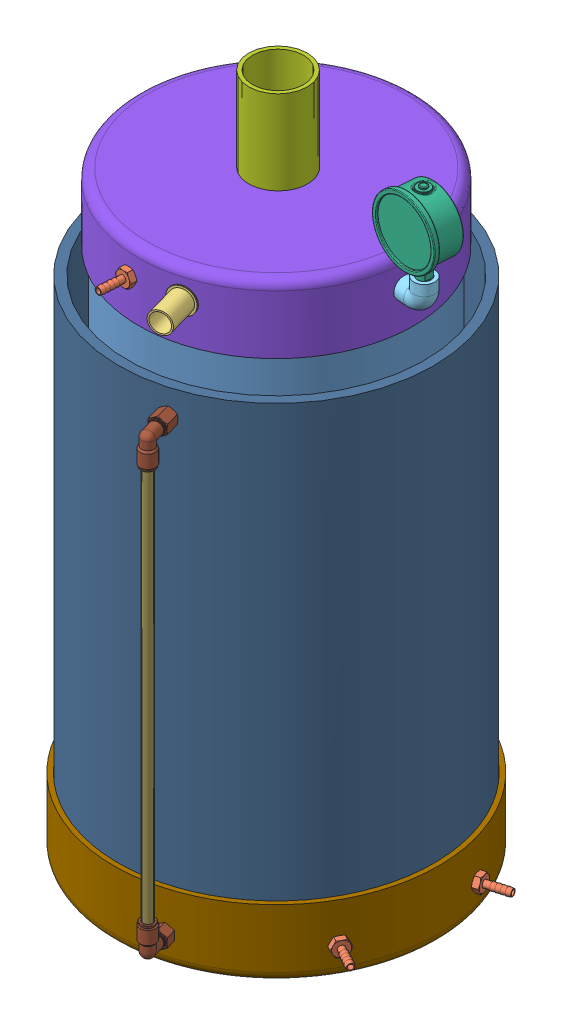
SolidWorks assembly GA, configuration Default. Lengths in mm.
Overall size (619.06 711.2 619.06).
27 component instances, 13 part files, 1 mates.
Components (placement in the parent):
- Top Assembly-1: Top Assembly [Default] at (-37.9382 248.6814 -16.604) size (344.44 711.2 318.42)
  - PI-002-1: PI-002 [Default<As Machined>] at (-41.0436 -593.4608 26.9612) x (0.997588 0 0.069407) z (0 -1 0) size (273.05 273.05 620)
  - 5372K112_DURABLE NYLON EXTRA-GRIP BARBED TUBE FITTING-1: 5372K112_DURABLE NYLON EXTRA-GRIP BARBED TUBE FITTING [5372K112] at (-51.4765 1.1392 176.914) x (-0.069407 0 0.997588) z (-0.863937 0.5 -0.060108) size (43.05 17.6 15.24)
  - 9173K740_THK-WALL DK GRAY PVC THRD-ONE-END PIPE NIPPLE-1: 9173K740_THK-WALL DK GRAY PVC THRD-ONE-END PIPE NIPPLE [9173K74] at (7.021 1.1392 194.3612) x (0.275974 0 0.961165) z (-0.72412 -0.657588 0.207913) size (51.34 27.61 27.43)
  - 4882K110_THICK-WALL DARK GRAY PVC THREADED PIPE NIPPLE-1: 4882K110_THICK-WALL DARK GRAY PVC THREADED PIPE NIPPLE [4882K11] at (101.258 1.1392 36.8618) x (0.997588 0 0.069407) z (-0.068883 -0.122609 0.990062) size (22.92 14.28 14.5)
  - 4596K121_THICK-WALL DARK GRAY PVC PIPE FITTING-1: 4596K121_THICK-WALL DARK GRAY PVC PIPE FITTING [4596K121] at (122.5425 1.1392 38.3427) x (0.997588 0 0.069407) z (-0.069407 0 0.997588) size (32.42 32.42 21.59)
  - 3795K133_STAINLESS STEEL GAUGE-1: 3795K133_STAINLESS STEEL GAUGE [3795K133] at (123.2653 70.4812 27.9538) x (0.997588 0 0.069407) z (-0.069407 0 0.997588) size (69.09 95.73 30.73)
  - PI-003-1: PI-003 [Default<As Machined>] at (-40.9313 -542.6608 25.2788) x (1 0 0) z (0 -1 0) size (60.32 60.32 660.4)
  - 2051K124_CHEMICAL-RESISTANT PVC DUCT - 10inch-3: 2051K124_CHEMICAL-RESISTANT PVC DUCT - 10inch [2051K124] at (-41.0436 -38.5483 26.9612) size (282.97 69.85 282.97)
- Bottom assembly-1: Bottom assembly [Default] at (-55.7763 -319.1166 13.4244) x (0.468435 0 -0.883498) z (-0.883498 0 -0.468435) size (457.9 512.76 457.9)
  - 2051K124_CHEMICAL-RESISTANT PVC DUCT-1: 2051K124_CHEMICAL-RESISTANT PVC DUCT [2051K124] at (-8.1604 -60.8789 21.9388) size (333.77 69.85 333.77)
  - PI-001-1: PI-001 [Default<As Machined>] at (-8.1604 -503.7914 21.9388) x (0.693013 0 -0.720925) z (-0.720925 0 -0.693013) size (323.85 508 323.85)
  - 5372K112_DURABLE NYLON EXTRA-GRIP BARBED TUBE FITTING-1: 5372K112_DURABLE NYLON EXTRA-GRIP BARBED TUBE FITTING [5372K112] at (113.5188 -21.1914 -104.6413) x (0.693013 0 -0.720925) z (-0.624339 0.5 -0.600167) size (43.05 17.6 15.24)
  - 5372K112_DURABLE NYLON EXTRA-GRIP BARBED TUBE FITTING-2: 5372K112_DURABLE NYLON EXTRA-GRIP BARBED TUBE FITTING [5372K112] at (-11.6267 -21.1914 -153.6505) x (-0.019737 0 -0.999805) z (0.865857 0.5 -0.017093) size (43.05 17.6 15.24)
  - 4882K110_THICK-WALL DARK GRAY PVC THREADED PIPE NIPPLE-1: 4882K110_THICK-WALL DARK GRAY PVC THREADED PIPE NIPPLE [4882K11] at (-124.7915 -21.1914 -90.1766) x (-0.720925 0 -0.693013) z (0.026932 0.999245 -0.028016) size (22.92 14.28 14.5)
  - 4882K110_THICK-WALL DARK GRAY PVC THREADED PIPE NIPPLE-2: 4882K110_THICK-WALL DARK GRAY PVC THREADED PIPE NIPPLE [4882K11] at (-124.7915 -478.3914 -90.1766) x (-0.720925 0 -0.693013) z (-0.121421 0.984531 0.126312) size (22.92 14.28 14.5)
  - 5779K638_PUSH-TO-CONNECT TUBE FITTING FOR AIR-1: 5779K638_PUSH-TO-CONNECT TUBE FITTING FOR AIR [5779K638] at (-124.7915 -478.3914 -90.1766) x (-0.693013 0 0.720925) z (0.720925 0 0.693013) size (16 35.65 39.07)
  - 5779K638_PUSH-TO-CONNECT TUBE FITTING FOR AIR-2: 5779K638_PUSH-TO-CONNECT TUBE FITTING FOR AIR [5779K638] at (-124.7915 -21.1914 -90.1766) x (0.693013 0 -0.720925) z (0.720925 0 0.693013) size (16 35.65 39.07)
  - 5233K520_MASTERKLEER PVC TUBING-1: 5233K520_MASTERKLEER PVC TUBING [5233K52] at (-146.8568 -252.8394 -111.3877) x (0 1 0) z (0.000774 0 1) size (410.46 9.53 9.53)
  - PI-004-1: PI-004 [Default<As Machined>] at (-8.4065 -97.3914 31.4606) x (0.958916 0 0.28369) z (-0.28369 0 0.958916) size (28.23 50.8 10.1)
  - PI-004-2: PI-004 [Default<As Machined>] at (-4.6725 -97.3914 13.0754) x (-0.958916 0 -0.28369) z (0.28369 0 -0.958916) size (28.23 50.8 10.1)
  - PI-004-3: PI-004 [Default<As Machined>] at (-17.4948 -97.3914 20.043) x (-0.28369 0 0.958916) z (-0.958916 0 -0.28369) size (28.23 50.8 10.1)
  - PI-004-4: PI-004 [Default<As Machined>] at (1.174 -97.3914 23.8346) x (0.28369 0 -0.958916) z (0.958916 0 0.28369) size (28.23 50.8 10.1)
  - PI-004-6: PI-004 [Default<As Machined>] at (-4.6725 -452.9914 13.0754) x (-0.958916 0 -0.28369) z (0.28369 0 -0.958916) size (28.23 50.8 10.1)
  - PI-004-9: PI-004 [Default<As Machined>] at (-17.4948 -452.9914 20.043) x (-0.28369 0 0.958916) z (-0.958916 0 -0.28369) size (28.23 50.8 10.1)
  - PI-004-13: PI-004 [Default<As Machined>] at (-8.4065 -452.9914 31.4606) x (0.958916 0 0.28369) z (-0.28369 0 0.958916) size (28.23 50.8 10.1)
  - PI-004-14: PI-004 [Default<As Machined>] at (1.174 -452.9914 23.8346) x (0.28369 0 -0.958916) z (0.958916 0 0.28369) size (28.23 50.8 10.1)
Mates (geometry in assembly coordinates):
- Concentric1: concentric anti-aligned: cylinder of Top Assembly-1/PI-002-1 through (-78.9819 275.2206 10.3572) axis (0 -1 0) radius 136.525; cylinder of Bottom assembly-1/PI-001-1 through (-78.9819 -323.3252 10.3572) axis (0 1 0) radius 161.925
